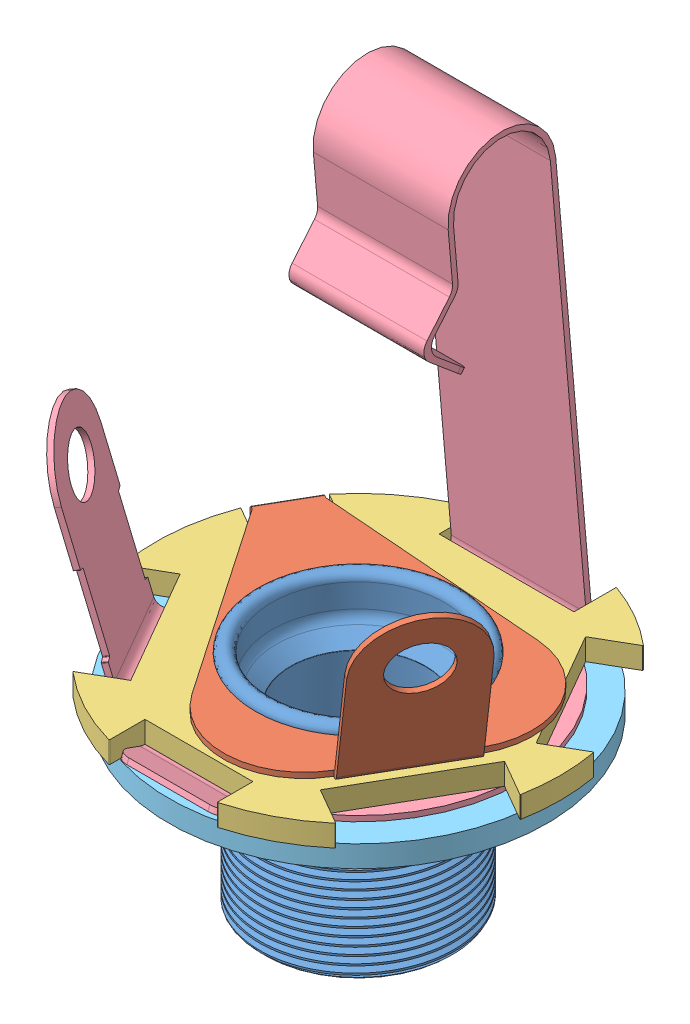
SolidWorks assembly FenderJack, configuration Default. Lengths in mm.
Overall size (21.76 31.52 19.89).
5 component instances, 5 part files, 0 mates.
Components (placement in the parent):
- FenderJack_Cylinder-1: FenderJack_Cylinder [Default] at (5.059 3.4811 15.0685) size (15.24 10.86 15.24)
- FenderJack_UpperTab-1: FenderJack_UpperTab [Default] at (5.059 13.4506 15.0685) x (0.866025 0 0.5) z (-0.5 0 0.866025) size (17.8 8.61 12.69)
- FenderJack_UpperSiPlate-1: FenderJack_UpperSiPlate [Default] at (5.059 12.4346 15.0685) size (19.05 1.02 18.14)
- FenderJack_LowerTab-1: FenderJack_LowerTab [Default] at (5.059 12.1806 15.0685) x (-1 0 0) z (0 0 -1) size (17.49 22.56 16.82)
- FenderJack_LowerSiPlate-1: FenderJack_LowerSiPlate [Default] at (5.059 11.1646 15.0685) size (17.78 1.02 17.78)
